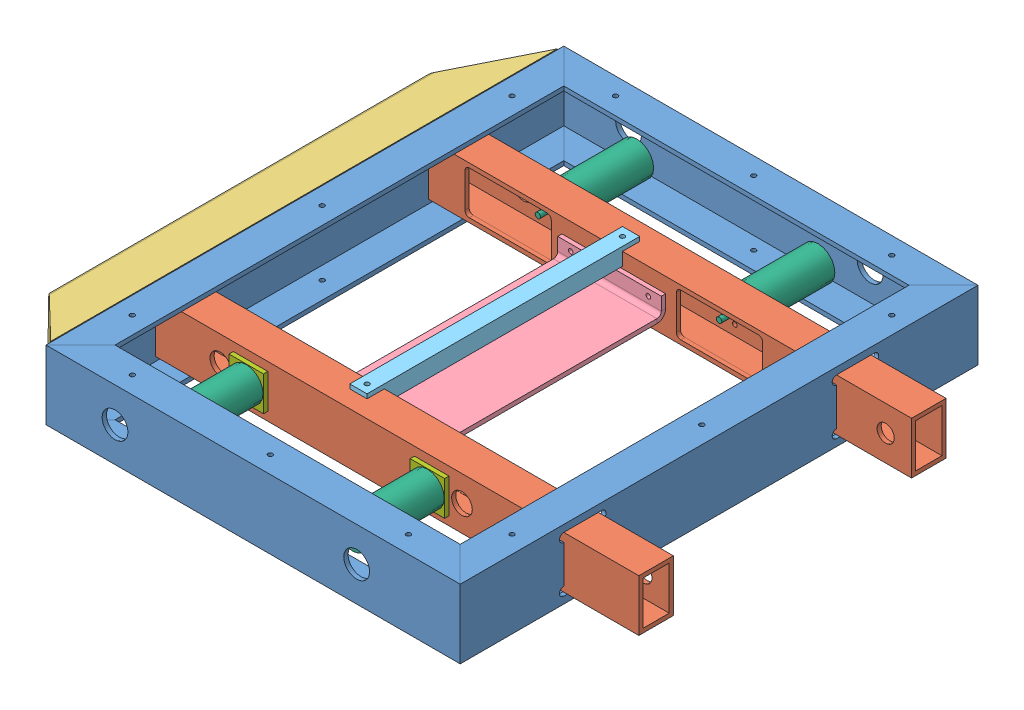
SolidWorks assembly Frame, configuration Default. Lengths in mm.
Overall size (411.9 66.35 381).
18 component instances, 7 part files, 53 mates.
Components (placement in the parent):
- Frame C-Channel-1: Frame C-Channel [Front] at (140.3478 189.2176 116.1664) x (0 1 0) z (0 0 1) size (50.8 25.4 381)
- Frame C-Channel-2: Frame C-Channel [Back] at (-164.4522 189.2176 116.1664) x (0 -1 0) z (0 0 1) size (50.8 25.4 381)
- Frame C-Channel-3: Frame C-Channel [Side] at (140.3478 189.2176 116.1664) x (0 -1 0) z (-1 0 0) size (50.8 25.4 304.8)
- Frame C-Channel-4: Frame C-Channel [Side] at (140.3478 189.2176 497.1664) x (0 1 0) z (-1 0 0) size (50.8 25.4 304.8)
- Roller Arm-1: Roller Arm [Motor] at (-161.2772 189.2176 206.3364) x (1 0 0) z (0 0 -1) size (355.6 38.1 25.4)
- Roller Arm-2: Roller Arm [Default] at (-161.2772 189.2176 406.9964) size (355.6 38.1 25.4)
- Rear Bumper-1: Rear Bumper [Default] at (-194.3188 178.4172 306.2947) x (0 0 -1) z (0.896344 -0.44336 0) size (378.57 44.9 57.7)
- Electronics Tray-1: Electronics Tray [Default] at (-24.7522 181.2801 306.6664) x (0 0 1) z (-1 0 0) size (175.26 15.88 76.2)
- Cross Brace-1: Cross Brace [Default] at (-18.4022 211.4426 406.9964) x (0 -1 0) z (0 0 -1) size (12.7 12.7 200.66)
- Cross Brace-2: Cross Brace [Default] at (-18.4022 166.9926 206.3364) x (0 1 0) z (0 0 1) size (12.7 12.7 200.66)
- Motor-1: Motor [Default] at (-91.4272 189.2176 208.2614) x (0 0 -1) z (1 0 0) size (72.8 24.8 24.8)
- Motor-2: Motor [Default] at (41.9228 189.2176 405.0714) x (0 0 1) z (-1 0 0) size (72.8 24.8 24.8)
- Motor-3: Motor [Default] at (41.9228 189.2176 208.2614) x (0 0 -1) z (1 0 0) size (72.8 24.8 24.8)
- Motor-4: Motor [Default] at (-91.4272 189.2176 405.0714) x (0 0 1) z (-1 0 0) size (72.8 24.8 24.8)
- Motor Mount-1: Motor Mount [Default] at (-91.4272 189.2176 419.6964) x (-1 0 0) z (0 1 0) size (25.4 3.17 25.4)
- Motor Mount-2: Motor Mount [Default] at (-91.4272 189.2176 193.6364) x (1 0 0) z (0 1 0) size (25.4 3.17 25.4)
- Motor Mount-3: Motor Mount [Default] at (41.9228 189.2176 419.6964) x (-1 0 0) z (0 1 0) size (25.4 3.17 25.4)
- Motor Mount-4: Motor Mount [Default] at (41.9228 189.2176 193.6364) x (1 0 0) z (0 1 0) size (25.4 3.17 25.4)
Mates (geometry in assembly coordinates):
- Coincident4: coincident aligned: line of Frame C-Channel-1 through (140.3478 163.8176 497.1664) axis (0 1 0); line of Frame C-Channel-4 through (140.3478 163.8176 497.1664) axis (0 1 0)
- Coincident5: coincident anti-aligned: plane of Frame C-Channel-1 through (140.3478 163.8176 497.1664) normal (-0.707107 0 0.707107); plane of Frame C-Channel-4 through (114.9478 163.8176 471.7664) normal (0.707107 0 -0.707107)
- Coincident6: coincident aligned: plane of Frame C-Channel-1 through (140.3478 214.6176 497.1664) normal (0 1 0); plane of Frame C-Channel-4 through (-164.4522 214.6176 497.1664) normal (0 1 0)
- Coincident7: coincident anti-aligned: line of Frame C-Channel-1 through (140.3478 163.8176 116.1664) axis (0 1 0); line of Frame C-Channel-3 through (140.3478 214.6176 116.1664) axis (0 -1 0)
- Coincident8: coincident anti-aligned: plane of Frame C-Channel-1 through (114.9478 163.8176 141.5664) normal (-0.707107 0 -0.707107); plane of Frame C-Channel-3 through (114.9478 214.6176 141.5664) normal (0.707107 0 0.707107)
- Coincident9: coincident aligned: plane of Frame C-Channel-1 through (140.3478 214.6176 497.1664) normal (0 1 0); plane of Frame C-Channel-3 through (-164.4522 214.6176 141.5664) normal (0 1 0)
- Coincident10: coincident aligned: line of Frame C-Channel-2 through (-164.4522 214.6176 116.1664) axis (0 -1 0); line of Frame C-Channel-3 through (-164.4522 214.6176 116.1664) axis (0 -1 0)
- Coincident11: coincident anti-aligned: line of Frame C-Channel-2 through (-164.4522 214.6176 497.1664) axis (0 -1 0); line of Frame C-Channel-4 through (-164.4522 163.8176 497.1664) axis (0 1 0)
- Coincident12: coincident aligned: plane of Frame C-Channel-2 through (-139.0522 214.6176 497.1664) normal (0 1 0); plane of Frame C-Channel-4 through (-164.4522 214.6176 497.1664) normal (0 1 0)
- Coincident13: coincident anti-aligned: plane of Frame C-Channel-2 through (-161.2772 166.9926 497.1664) normal (1 0 0); plane of Roller Arm-2 through (-161.2772 189.2176 406.9964) normal (-1 0 0)
- Width1: width anti-aligned: plane of Roller Arm-2 through (194.3228 170.1676 419.6964) normal (0 0 1); plane of Roller Arm-2 through (194.3228 170.1676 394.2964) normal (0 0 -1); plane of Frame C-Channel-1 through (114.9478 175.2476 420.9664) normal (0 0 -1); plane of Frame C-Channel-1 through (114.9478 175.2476 393.0264) normal (0 0 1)
- Width2: width anti-aligned: plane of Roller Arm-2 through (194.3228 170.1676 419.6964) normal (0 -1 0); plane of Roller Arm-2 through (194.3228 208.2676 419.6964) normal (0 1 0); plane of Frame C-Channel-1 through (114.9478 168.8976 393.0264) normal (0 1 0); plane of Frame C-Channel-1 through (114.9478 209.5376 393.0264) normal (0 -1 0)
- Coincident14: coincident anti-aligned: plane of Frame C-Channel-2 through (-161.2772 166.9926 497.1664) normal (1 0 0); plane of Roller Arm-1 through (-161.2772 189.2176 206.3364) normal (-1 0 0)
- Width6: width anti-aligned: plane of Roller Arm-1 through (194.3228 208.2676 193.6364) normal (0 0 -1); plane of Roller Arm-1 through (194.3228 208.2676 219.0364) normal (0 0 1); plane of Frame C-Channel-1 through (114.9478 175.2476 192.3664) normal (0 0 1); plane of Frame C-Channel-1 through (114.9478 175.2476 220.3064) normal (0 0 -1)
- Width7: width anti-aligned: plane of Frame C-Channel-1 through (114.9478 168.8976 220.3064) normal (0 1 0); plane of Frame C-Channel-1 through (114.9478 209.5376 220.3064) normal (0 -1 0); plane of Roller Arm-1 through (194.3228 170.1676 193.6364) normal (0 -1 0); plane of Roller Arm-1 through (194.3228 208.2676 193.6364) normal (0 1 0)
- Coincident18: coincident: plane of Frame C-Channel-2 through (-164.4522 214.6176 497.1664) normal (-1 0 0); line of Rear Bumper-1 through (-164.4522 211.2334 492.6464) axis (0 0 -1)
- Coincident19: coincident: plane of Frame C-Channel-2 through (-164.4522 214.6176 497.1664) normal (-1 0 0); line of Rear Bumper-1 through (-164.4522 167.1864 495.5797) axis (0 0 -1)
- Parallel2: parallel aligned: line of Frame C-Channel-2 through (-164.4522 214.6176 497.1664) axis (0 0 -1); line of Rear Bumper-1 through (-165.4692 214.2411 492.6464) axis (0 0 -1)
- Lock1: lock: unknown of Frame C-Channel-2; unknown of Rear Bumper-1
- Coincident21: coincident anti-aligned: plane of Roller Arm-2 through (194.3228 170.1676 394.2964) normal (0 0 -1); plane of Electronics Tray-1 through (-24.7522 181.2801 394.2964) normal (0 0 1)
- Parallel3: parallel aligned: plane of Roller Arm-2 through (194.3228 208.2676 419.6964) normal (0 1 0); plane of Electronics Tray-1 through (-62.8522 197.1551 394.2964) normal (0 1 0)
- Coincident22: coincident anti-aligned: plane of Roller Arm-2 through (194.3228 208.2676 419.6964) normal (0 1 0); plane of Cross Brace-1 through (-31.1022 208.2676 206.3364) normal (0 -1 0)
- Width8: width anti-aligned: plane of Cross Brace-1 through (-18.4022 211.4426 206.3364) normal (0 0 -1); plane of Cross Brace-1 through (-18.4022 211.4426 406.9964) normal (0 0 1); plane of Roller Arm-1 through (194.3228 208.2676 193.6364) normal (0 0 -1); plane of Roller Arm-2 through (194.3228 170.1676 419.6964) normal (0 0 1)
- Parallel4: parallel aligned: plane of Frame C-Channel-2 through (-161.2772 166.9926 497.1664) normal (1 0 0); plane of Cross Brace-1 through (-18.4022 198.7426 206.3364) normal (1 0 0)
- Coincident23: coincident anti-aligned: plane of Roller Arm-2 through (194.3228 170.1676 419.6964) normal (0 -1 0); plane of Cross Brace-2 through (-31.1022 170.1676 406.9964) normal (0 1 0)
- Width9: width anti-aligned: plane of Cross Brace-2 through (-18.4022 166.9926 206.3364) normal (0 0 -1); plane of Cross Brace-2 through (-18.4022 166.9926 406.9964) normal (0 0 1); plane of Roller Arm-2 through (194.3228 170.1676 419.6964) normal (0 0 1); plane of Roller Arm-1 through (194.3228 208.2676 193.6364) normal (0 0 -1)
- Coincident24: coincident aligned: plane of Cross Brace-1 through (-18.4022 198.7426 206.3364) normal (1 0 0); plane of Cross Brace-2 through (-18.4022 179.6926 406.9964) normal (1 0 0)
- Width10: width anti-aligned: plane of Cross Brace-1 through (-31.1022 211.4426 206.3364) normal (-1 0 0); plane of Cross Brace-1 through (-18.4022 198.7426 206.3364) normal (1 0 0); plane of Roller Arm-1 through (21.2853 201.9176 193.6354) normal (1 0 0); plane of Roller Arm-1 through (-70.7897 201.9176 193.6354) normal (-1 0 0)
- Concentric2: concentric aligned: cylinder of Roller Arm-2 through (-53.3272 192.3926 394.2964) axis (0 0 -1) radius 1.7; cylinder of Electronics Tray-1 through (-53.3272 192.3926 219.0364) axis (0 0 -1) radius 1.7
- Coincident25: coincident anti-aligned: plane of Motor-1 through (-91.4272 193.2176 190.4614) normal (0 0 1); plane of Motor Mount-2 through (-91.4272 189.2176 190.4614) normal (0 0 -1)
- Coincident26: coincident anti-aligned: plane of Motor-4 through (-91.4272 193.2176 422.8714) normal (0 0 -1); plane of Motor Mount-1 through (-91.4272 189.2176 422.8714) normal (0 0 1)
- Coincident27: coincident anti-aligned: plane of Motor-2 through (41.9228 193.2176 422.8714) normal (0 0 -1); plane of Motor Mount-3 through (41.9228 189.2176 422.8714) normal (0 0 1)
- Coincident28: coincident anti-aligned: plane of Motor-3 through (41.9228 193.2176 190.4614) normal (0 0 1); plane of Motor Mount-4 through (41.9228 189.2176 190.4614) normal (0 0 -1)
- Concentric3: concentric anti-aligned: cylinder of Motor-3 through (41.9228 197.7176 185.4614) axis (0 0 1) radius 1.5; cylinder of Motor Mount-4 through (41.9228 197.7176 190.4614) axis (0 0 -1) radius 1.7
- Concentric4: concentric anti-aligned: cylinder of Motor-3 through (41.9228 180.7176 185.4614) axis (0 0 1) radius 1.5; cylinder of Motor Mount-4 through (41.9228 180.7176 190.4614) axis (0 0 -1) radius 1.7
- Concentric5: concentric anti-aligned: cylinder of Motor-2 through (41.9228 197.7176 427.8714) axis (0 0 -1) radius 1.5; cylinder of Motor Mount-3 through (41.9228 197.7176 422.8714) axis (0 0 1) radius 1.7
- Concentric6: concentric anti-aligned: cylinder of Motor-2 through (41.9228 180.7176 427.8714) axis (0 0 -1) radius 1.5; cylinder of Motor Mount-3 through (41.9228 180.7176 422.8714) axis (0 0 1) radius 1.7
- Concentric7: concentric anti-aligned: cylinder of Motor-4 through (-91.4272 197.7176 427.8714) axis (0 0 -1) radius 1.5; cylinder of Motor Mount-1 through (-91.4272 197.7176 422.8714) axis (0 0 1) radius 1.7
- Concentric8: concentric anti-aligned: cylinder of Motor-4 through (-91.4272 180.7176 427.8714) axis (0 0 -1) radius 1.5; cylinder of Motor Mount-1 through (-91.4272 180.7176 422.8714) axis (0 0 1) radius 1.7
- Concentric9: concentric anti-aligned: cylinder of Motor-1 through (-91.4272 197.7176 185.4614) axis (0 0 1) radius 1.5; cylinder of Motor Mount-2 through (-91.4272 197.7176 190.4614) axis (0 0 -1) radius 1.7
- Concentric10: concentric anti-aligned: cylinder of Motor-1 through (-91.4272 180.7176 185.4614) axis (0 0 1) radius 1.5; cylinder of Motor Mount-2 through (-91.4272 180.7176 190.4614) axis (0 0 -1) radius 1.7
- Concentric11: concentric aligned: cylinder of Roller Arm-1 through (41.9228 197.7176 193.6364) axis (0 0 -1) radius 1.7; cylinder of Motor Mount-4 through (41.9228 197.7176 190.4614) axis (0 0 -1) radius 1.7
- Concentric12: concentric aligned: cylinder of Roller Arm-1 through (41.9228 180.7176 193.6364) axis (0 0 -1) radius 1.7; cylinder of Motor Mount-4 through (41.9228 180.7176 190.4614) axis (0 0 -1) radius 1.7
- Coincident29: coincident anti-aligned: plane of Roller Arm-1 through (194.3228 208.2676 193.6364) normal (0 0 -1); plane of Motor Mount-4 through (41.9228 189.2176 193.6364) normal (0 0 1)
- Concentric13: concentric aligned: cylinder of Roller Arm-1 through (-91.4272 197.7176 193.6364) axis (0 0 -1) radius 1.7; cylinder of Motor Mount-2 through (-91.4272 197.7176 190.4614) axis (0 0 -1) radius 1.7
- Concentric14: concentric aligned: cylinder of Roller Arm-1 through (-91.4272 180.7176 193.6364) axis (0 0 -1) radius 1.7; cylinder of Motor Mount-2 through (-91.4272 180.7176 190.4614) axis (0 0 -1) radius 1.7
- Coincident30: coincident anti-aligned: plane of Roller Arm-1 through (194.3228 208.2676 193.6364) normal (0 0 -1); plane of Motor Mount-2 through (-91.4272 189.2176 193.6364) normal (0 0 1)
- Concentric15: concentric aligned: cylinder of Roller Arm-2 through (41.9228 197.7176 419.6964) axis (0 0 1) radius 1.7; cylinder of Motor Mount-3 through (41.9228 197.7176 422.8714) axis (0 0 1) radius 1.7
- Concentric16: concentric aligned: cylinder of Roller Arm-2 through (41.9228 180.7176 419.6964) axis (0 0 1) radius 1.7; cylinder of Motor Mount-3 through (41.9228 180.7176 422.8714) axis (0 0 1) radius 1.7
- Coincident31: coincident anti-aligned: plane of Roller Arm-2 through (194.3228 170.1676 419.6964) normal (0 0 1); plane of Motor Mount-3 through (41.9228 189.2176 419.6964) normal (0 0 -1)
- Concentric17: concentric aligned: cylinder of Roller Arm-2 through (-91.4272 197.7176 419.6964) axis (0 0 1) radius 1.7; cylinder of Motor Mount-1 through (-91.4272 197.7176 422.8714) axis (0 0 1) radius 1.7
- Concentric18: concentric aligned: cylinder of Roller Arm-2 through (-91.4272 180.7176 419.6964) axis (0 0 1) radius 1.7; cylinder of Motor Mount-1 through (-91.4272 180.7176 422.8714) axis (0 0 1) radius 1.7
- Coincident32: coincident anti-aligned: plane of Roller Arm-2 through (194.3228 170.1676 419.6964) normal (0 0 1); plane of Motor Mount-1 through (-91.4272 189.2176 419.6964) normal (0 0 -1)
